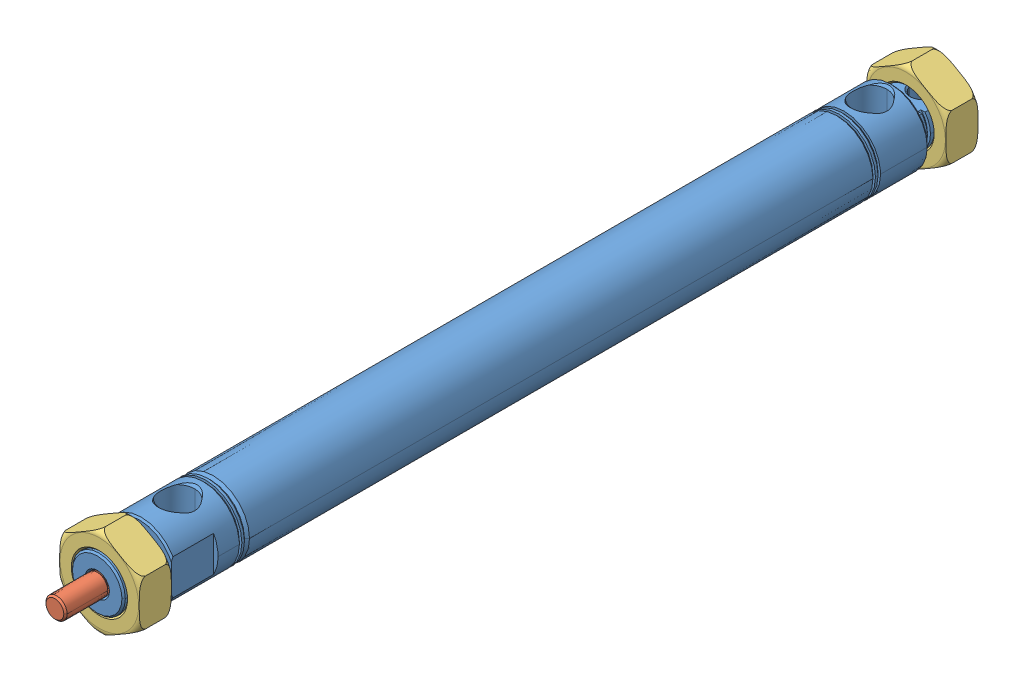
SolidWorks assembly Pressure_Cylinder, configuration Default. Lengths in mm.
Overall size (27.58 27.58 267.46).
5 component instances, 3 part files, 0 mates.
Components (placement in the parent):
- Pressure_Cylinder.STEP-1: Pressure_Cylinder.STEP [Default] at origin size (27.58 27.58 267.46)
  - NCME075-0600.step_NCM-Body_075E.STEP-1: NCME075-0600.step_NCM-Body_075E.STEP [Default] at origin size (21.84 21.85 254.76)
  - NCME075-0600.step_NCM-Rod_075.STEP-1: NCME075-0600.step_NCM-Rod_075.STEP [Default] at (0 0 -76.2) x (-1 0 0) z (0 0 1) size (19.05 19.05 225.13)
  - NCME075-0600.step_NCM-Nut_075.STEP-1: NCME075-0600.step_NCM-Nut_075.STEP [Default] at (0 0 128.239) x (-1 0 0) z (0 0 1) size (27.58 27.58 9.66)
  - NCME075-0600.step_NCM-Nut_075.STEP-2: NCME075-0600.step_NCM-Nut_075.STEP [Default] at (0 0 -113.919) size (27.58 27.58 9.66)
